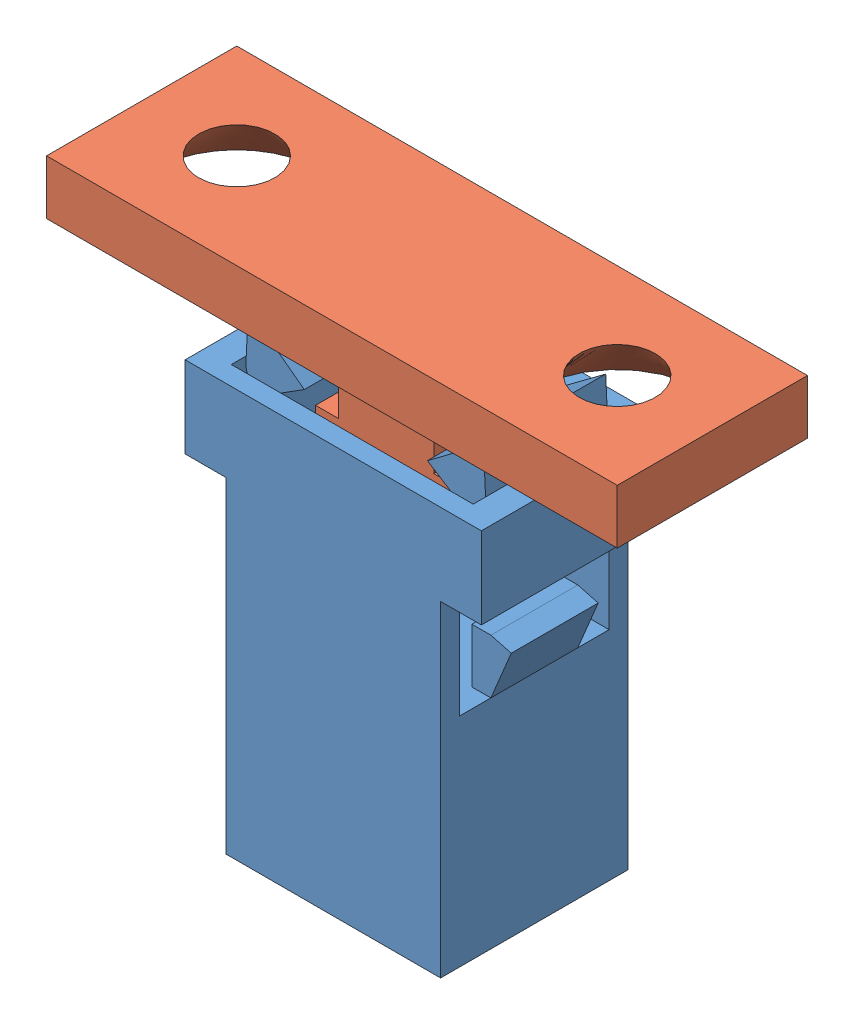
SolidWorks assembly touch_clamp, configuration Closed. Lengths in mm.
Overall size (21.45 19 7).
2 component instances, 2 part files, 4 mates.
Components (placement in the parent):
- touch_clamp-1: touch_clamp [Closed] at origin size (10.9 16.59 6.9)
- touch_plate-1: touch_plate [Default] at (0 19 0) x (-1 0 0) z (0 0 1)
Mates (geometry in assembly coordinates):
- Coincident1: coordinate: point of touch_clamp-1
- Coincident2: coincident anti-aligned: plane of touch_clamp-1 through (-1.25 11.7 7.9531) normal (0 1 0); plane of touch_plate-1 through (1.3 11.7 7.1859) normal (0 -1 0)
- Width1: width anti-aligned: plane of touch_clamp-1 through (-4.45 8 2.25) normal (0 0 1); plane of touch_clamp-1 through (-4.45 8 -2.25) normal (0 0 -1); plane of touch_plate-1 through (1.75 14 -1.5) normal (0 0 -1); plane of touch_plate-1 through (1.75 14 1.5) normal (0 0 1)
- Width2: width aligned: plane of touch_clamp-1 through (-5.45 15 3.45) normal (-1 0 0); plane of touch_clamp-1 through (5.45 15 3.45) normal (1 0 0); plane of touch_plate-1 through (-10.5 17 3.5) normal (-1 0 0); plane of touch_plate-1 through (10.5 17 3.5) normal (1 0 0)
